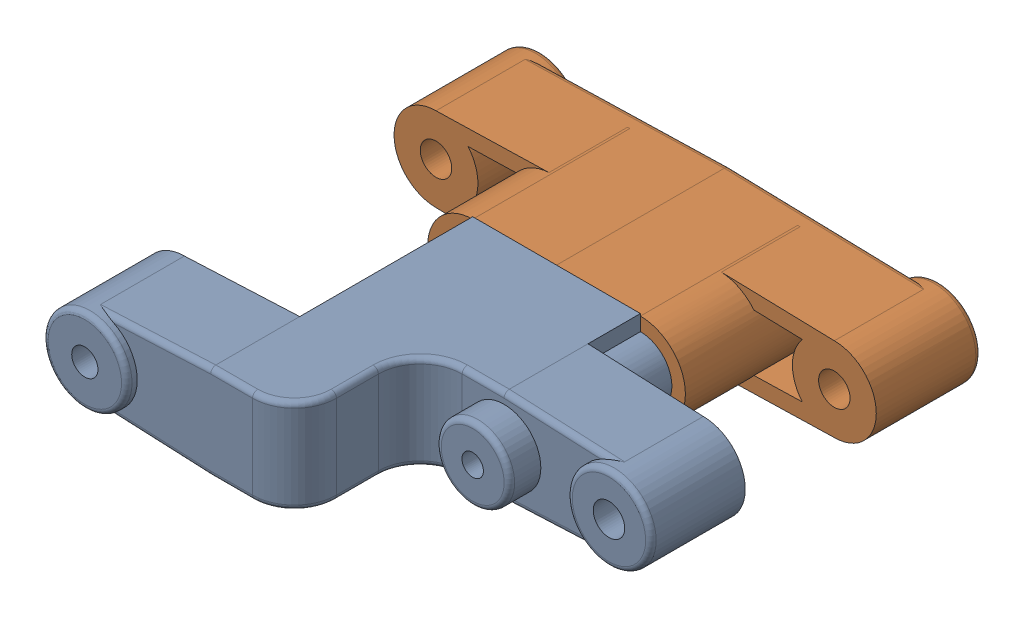
SolidWorks assembly Triangle arrière, configuration Défaut. Lengths in mm.
Overall size (46 9 43.5).
4 component instances, 3 part files, 7 mates.
Components (placement in the parent):
- Triangle arrière-C15-1: Triangle arrière-C15 [Défaut] at origin size (46 9 34)
- Triangle arrière-C14-1: Triangle arrière-C14 [Défaut] at (0 0 -7.5) x (-1 0 0) z (0 0 -1) size (46 9 17.5)
- Vis-M3-10-1: Vis-M3-10 [Défaut] at (-8 0 -8.5) x (-0.631582 0.775309 0) z (0 0 -1) size (4.92 4.92 11.54)
- Vis-M3-10-2: Vis-M3-10 [Défaut] at (8 0 -8.5) x (0.97993 -0.199344 0) z (0 0 -1) size (4.92 4.92 11.54)
Mates (geometry in assembly coordinates):
- Coïncidente1: coincident anti-aligned: axis of Triangle arrière-C15-1 through (-8 0 0.5) axis (0 0 -1); axis of Triangle arrière-C14-1 through (-8 0 -8) axis (0 0 1)
- Coïncidente2: coincident aligned: axis of Triangle arrière-C15-1 through (8 0 0.5) axis (0 0 -1); axis of Triangle arrière-C14-1 through (8 0 -7.5) axis (0 0 -1)
- Coïncidente3: coincident anti-aligned: plane of Triangle arrière-C15-1 through (8 0 0) normal (0 0 -1); plane of Triangle arrière-C14-1 through (-8 0 0) normal (0 0 1)
- Coïncidente4: coincident anti-aligned: plane of Triangle arrière-C14-1 through (8 0 -8.5) normal (0 0 -1); plane of Vis-M3-10-2
- Coïncidente5: coincident anti-aligned: plane of Triangle arrière-C14-1 through (-8 0 -8.5) normal (0 0 -1); plane of Vis-M3-10-1
- Coïncidente6: coincident aligned: axis of Triangle arrière-C15-1 through (-8 0 16.5) axis (0 0 -1); axis of Vis-M3-10-1 through (-8 0 1) axis (0 0 -1)
- Coïncidente7: coincident aligned: axis of Triangle arrière-C15-1 through (8 0 15.5) axis (0 0 -1); axis of Vis-M3-10-2 through (8 0 1) axis (0 0 -1)
